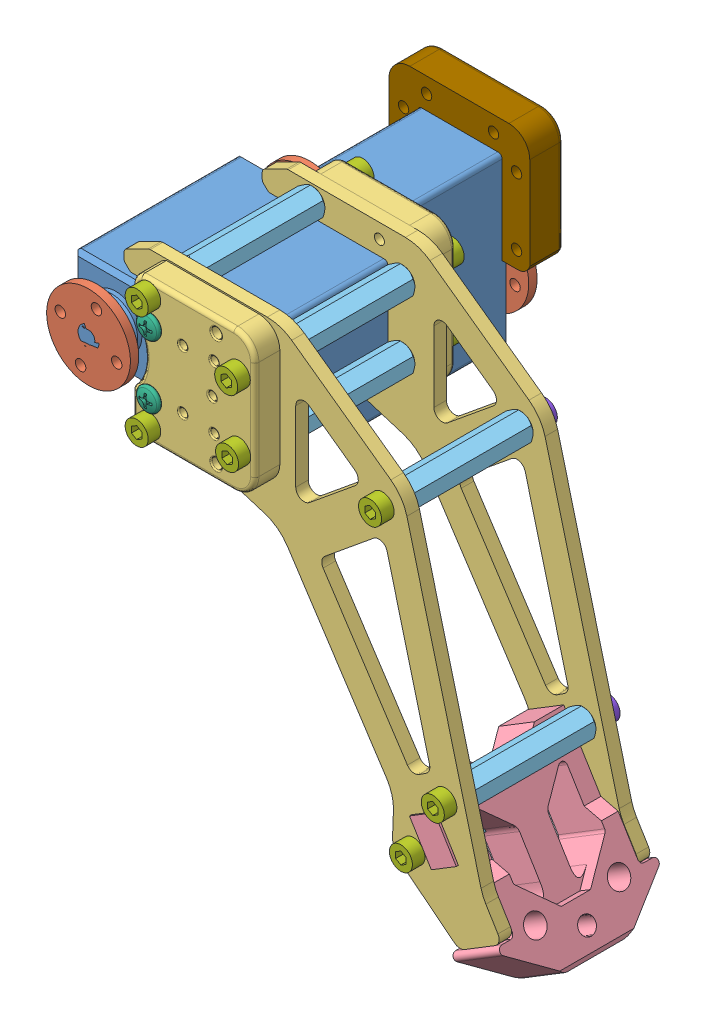
SolidWorks assembly ServoASM, configuration По умолчанию. Lengths in mm.
Overall size (131.49 117.47 116.79).
37 component instances, 9 part files, 80 mates.
Components (placement in the parent):
- RDS3115MG-1: RDS3115MG [00] at origin size (40 20 52)
- Servo_Disk_25T-1: Servo_Disk_25T [00] at (-10 0 46.5) x (-0.87183 -0.489808 0) z (0.489808 -0.87183 0) size (20 4.5 20)
- Servo_Disk_25T-2: Servo_Disk_25T [00] at (-10 0 -6.4) x (0.87183 0.489808 0) z (0.489808 -0.87183 0) size (20 4.5 20)
- Tibia_side_plate-1: Tibia_side_plate [Défaut] at (7.75 0 2) size (89.6 107.6 3)
- Foot-1: Foot [Défaut] at (59.1952 -69.5736 20) x (0 0 -1) z (0.853181 0.521616 0) size (37.94 40 13.02)
- Tibia_side_plate-3: Tibia_side_plate [Défaut] at (7.75 0 35) size (89.6 107.6 3)
- Tibia_side_plate-4: Tibia_side_plate [right] at (7.75 0 38) x (1 0 0) z (0 0 -1) size (29.2 33.65 6)
- Tibia_side_plate-5: Tibia_side_plate [right] at (7.75 0 2) size (29.2 33.65 6)
- Standoff-1: Standoff [Défaut] at (51.75 -8.1461 5) size (6 7.62 30)
- Standoff-2: Standoff [Défaut] at (59.1257 -75.9595 5) size (6 7.62 30)
- Standoff-3: Standoff [Défaut] at (66.75 -61.8929 5) size (6 7.62 30)
- BHS_M2_6X8-1: BHS_M2_6X8 [Défaut] at (2.5 7.5 44) x (1 0 0) z (0 -1 0) size (5.5 9.6 5.5)
- BHS_M2_6X8-2: BHS_M2_6X8 [Défaut] at (2.5 -7.5 44) x (1 0 0) z (0 -1 0) size (5.5 9.6 5.5)
- BHS_M2_6X8-4: BHS_M2_6X8 [Défaut] at (10 7 -4) x (-0.923728 -0.383049 0) z (0.383049 -0.923728 0) size (5.5 9.6 5.5)
- BHS_M2_6X8-5: BHS_M2_6X8 [Défaut] at (10 -7 -4) x (-0.923728 -0.383049 0) z (0.383049 -0.923728 0) size (5.5 9.6 5.5)
- M3x10-1: M3x10 [00] at (2 -13.5 44) size (5.5 5.5 13.08)
- M3x10-2: M3x10 [00] at (23.5 -8 43.8922) size (5.5 5.5 13.08)
- M3x10-3: M3x10 [00] at (2 13.5 44) size (5.5 5.5 13.08)
- M3x10-4: M3x10 [00] at (23.5 8 44.1078) size (5.5 5.5 13.08)
- M3x8-7: M3x8 [00] at (59.1257 -75.9595 2) x (-0.923728 -0.383049 0) z (0 0 -1) size (5.5 5.5 11.08)
- M3x8-8: M3x8 [00] at (51.75 -8.1461 2) x (-0.923728 -0.383049 0) z (0 0 -1) size (5.5 5.5 11.08)
- M3x8-9: M3x8 [00] at (66.75 -61.8929 2) x (-0.923728 -0.383049 0) z (0 0 -1) size (5.5 5.5 11.08)
- M3x10-5: M3x10 [00] at (51.75 -8.1461 38) size (5.5 5.5 13.08)
- M3x10-6: M3x10 [00] at (66.75 -61.8929 38) size (5.5 5.5 13.08)
- M3x10-7: M3x10 [00] at (59.1257 -75.9595 38) size (5.5 5.5 13.08)
- M3x10-8: M3x10 [00] at (23.5 8 -4) x (-0.923728 -0.383049 0) z (0 0 -1) size (5.5 5.5 13.08)
- M3x10-9: M3x10 [00] at (2 -13.5 -4) x (-0.923728 -0.383049 0) z (0 0 -1) size (5.5 5.5 13.08)
- M3x10-10: M3x10 [00] at (23.5 -8 -4) x (-0.923728 -0.383049 0) z (0 0 -1) size (5.5 5.5 13.08)
- M3x10-11: M3x10 [00] at (2 13.5 -4) x (-0.923728 -0.383049 0) z (0 0 -1) size (5.5 5.5 13.08)
- Standoff-4: Standoff [Défaut] at (23.5 8 5) size (6 7.62 30)
- Standoff-5: Standoff [Défaut] at (23.5 -8 5) size (6 7.62 30)
- Standoff-6: Standoff [Défaut] at (2 -13.5 5) size (6 7.62 30)
- Standoff-7: Standoff [Défaut] at (2 13.5 5) size (6 7.62 30)
- RDS3115MG-2: RDS3115MG [00] at (-29.0274 -40.5678 -63.286) x (0 1 0) z (0 0 1) size (40 20 52)
- Servo_Disk_25T-3: Servo_Disk_25T [00] at (-29.0274 -50.5678 -69.686) x (0.87183 0.489808 0) z (0.489808 -0.87183 0) size (20 4.5 20)
- Servo_Disk_25T-4: Servo_Disk_25T [00] at (-29.0274 -50.5678 -16.786) x (-0.87183 -0.489808 0) z (0.489808 -0.87183 0) size (20 4.5 20)
- Tibia_side_plate2-1: Tibia_side_plate2 [two] at (-29.0274 -32.8178 -61.286) x (0 1 0) z (0 0 1) size (29.2 33.65 8)
Mates (geometry in assembly coordinates):
- Концентричный1: concentric aligned: cylinder of RDS3115MG-1 through (-10 0 40) axis (0 0 1) radius 3; cylinder of Servo_Disk_25T-1 through (-10 0 42) axis (0 0 1) radius 4.5
- Совпадение1: coincident anti-aligned: plane of RDS3115MG-1 through (-10 0 42) normal (0 0 1); plane of Servo_Disk_25T-1 through (-10 0 42) normal (0 0 -1)
- Концентричный2: concentric anti-aligned: cylinder of RDS3115MG-1 through (-10 0 -10.6191) axis (0 0 1) radius 1; cylinder of Servo_Disk_25T-2 through (-10 0 -1.9) axis (0 0 -1) radius 4.5
- Совпадение2: coincident anti-aligned: plane of RDS3115MG-1 through (-10 0 -5.5) normal (0 0 -1); plane of Servo_Disk_25T-2 through (-10 0 -5.5) normal (0 0 1)
- Концентричный3: concentric anti-aligned: cylinder of Servo_Disk_25T-1 through (-3.2602 -1.8909 44.5) axis (0 0 -1) radius 1.25; cylinder of Servo_Disk_25T-2 through (-3.2602 -1.8909 -4.4) axis (0 0 1) radius 1.25
- Концентричный4: concentric anti-aligned: cylinder of Tibia_side_plate-1 through (18 13.5 5) axis (0 0 1) radius 1.2; cylinder of Tibia_side_plate-5 through (18 13.5 5.5355) axis (0 0 -1) radius 1.25
- Концентричный5: concentric aligned: cylinder of Tibia_side_plate-1 through (2 -13.5 8.3941) axis (0 0 -1) radius 1.2; cylinder of Tibia_side_plate-5 through (2 -13.5 5.5355) axis (0 0 -1) radius 1.25
- Совпадение14: coincident anti-aligned: plane of Tibia_side_plate-1 through (7.75 0 2) normal (0 0 -1); plane of Tibia_side_plate-5 through (1 14 2) normal (0 0 1)
- Концентричный6: concentric aligned: cylinder of Tibia_side_plate-3 through (18 13.5 38) axis (0 0 1) radius 1.2; cylinder of Tibia_side_plate-4 through (18 13.5 34.4645) axis (0 0 1) radius 1.25
- Концентричный7: concentric anti-aligned: cylinder of Tibia_side_plate-3 through (2 -13.5 41.3941) axis (0 0 -1) radius 1.2; cylinder of Tibia_side_plate-4 through (2 -13.5 34.4645) axis (0 0 1) radius 1.25
- Совпадение15: coincident anti-aligned: plane of Tibia_side_plate-3 through (7.75 0 38) normal (0 0 1); plane of Tibia_side_plate-4 through (1 -14 38) normal (0 0 -1)
- Ширина3: width anti-aligned: plane of RDS3115MG-1 through (20 10 0) normal (0 1 0); plane of RDS3115MG-1 through (-20 -10 0) normal (0 -1 0); plane of Tibia_side_plate-3 through (7.75 10 38) normal (0 -1 0); plane of Tibia_side_plate-3 through (7.75 -10 38) normal (0 1 0)
- Ширина4: width aligned: plane of RDS3115MG-1 through (-20 -10 0) normal (0 -1 0); plane of RDS3115MG-1 through (20 10 0) normal (0 1 0); plane of Tibia_side_plate-1 through (7.75 10 5) normal (0 -1 0); plane of Tibia_side_plate-1 through (7.75 -10 5) normal (0 1 0)
- Концентричный8: concentric aligned: cylinder of RDS3115MG-1 through (17.5 7.5 40) axis (0 0 -1) radius 1; cylinder of Tibia_side_plate-4 through (17.5 7.5 44) axis (0 0 -1) radius 1
- Концентричный9: concentric aligned: cylinder of RDS3115MG-1 through (2.5 -7.5 40) axis (0 0 -1) radius 1; cylinder of Tibia_side_plate-4 through (2.5 -7.5 44) axis (0 0 -1) radius 1
- Концентричный10: concentric aligned: cylinder of RDS3115MG-1 through (10 7 0) axis (0 0 1) radius 1; cylinder of Tibia_side_plate-5 through (10 7 -4) axis (0 0 1) radius 1
- Концентричный11: concentric aligned: cylinder of RDS3115MG-1 through (10 -7 0) axis (0 0 1) radius 1; cylinder of Tibia_side_plate-5 through (10 -7 -4) axis (0 0 1) radius 1
- Совпадение16: coincident anti-aligned: plane of RDS3115MG-1 through (0 0 0) normal (0 0 -1); plane of Tibia_side_plate-5 through (1 14 0) normal (0 0 1)
- Совпадение17: coincident anti-aligned: plane of RDS3115MG-1 through (0 0 40) normal (0 0 1); plane of Tibia_side_plate-4 through (1 -14 40) normal (0 0 -1)
- Совпадение18: coincident anti-aligned: plane of Foot-1 through (59.1952 -69.5736 20) normal (-0.853181 -0.521616 0); plane of Tibia_side_plate-3 through (58.6736 -68.7204 34.999) normal (0.853181 0.521616 0)
- Совпадение19: coincident anti-aligned: plane of Tibia_side_plate-1 through (58.6736 -68.7204 1.999) normal (0.853181 0.521616 0); plane of Foot-1 through (59.1952 -69.5736 20) normal (-0.853181 -0.521616 0)
- Совпадение20: coincident anti-aligned: plane of Foot-1 through (64.6459 -65.0691 20) normal (-0.521616 0.853181 0); plane of Tibia_side_plate-3 through (58.6736 -68.7204 34.999) normal (0.521616 -0.853181 0)
- Ширина5: width aligned: plane of Foot-1 through (59.1952 -69.5736 35) normal (0 0 1); plane of Foot-1 through (59.1952 -69.5736 5) normal (0 0 -1); plane of Tibia_side_plate-1 through (7.75 0 5) normal (0 0 1); plane of Tibia_side_plate-3 through (7.75 0 35) normal (0 0 -1)
- Концентричный12: concentric aligned: cylinder of Tibia_side_plate-3 through (51.75 -8.1461 35) axis (0 0 -1) radius 1.7; cylinder of Standoff-1 through (51.75 -8.1461 5) axis (0 0 -1) radius 1.25
- Ширина6: width aligned: plane of Tibia_side_plate-1 through (7.75 0 5) normal (0 0 1); plane of Tibia_side_plate-3 through (7.75 0 35) normal (0 0 -1); plane of Standoff-1 through (51.75 -8.1461 35) normal (0 0 1); plane of Standoff-1 through (51.75 -8.1461 5) normal (0 0 -1)
- Ширина7: width aligned: plane of Tibia_side_plate-1 through (7.75 0 5) normal (0 0 1); plane of Tibia_side_plate-3 through (7.75 0 35) normal (0 0 -1); plane of Standoff-3 through (66.75 -61.8929 35) normal (0 0 1); plane of Standoff-3 through (66.75 -61.8929 5) normal (0 0 -1)
- Ширина8: width aligned: plane of Tibia_side_plate-3 through (7.75 0 35) normal (0 0 -1); plane of Tibia_side_plate-1 through (7.75 0 5) normal (0 0 1); plane of Standoff-2 through (59.1257 -75.9595 5) normal (0 0 -1); plane of Standoff-2 through (59.1257 -75.9595 35) normal (0 0 1)
- Концентричный13: concentric aligned: cylinder of Tibia_side_plate-3 through (59.1257 -75.9595 35) axis (0 0 -1) radius 1.7; cylinder of Standoff-2 through (59.1257 -75.9595 5) axis (0 0 -1) radius 1.25
- Концентричный14: concentric aligned: cylinder of Tibia_side_plate-3 through (66.75 -61.8929 35) axis (0 0 -1) radius 1.7; cylinder of Standoff-3 through (66.75 -61.8929 5) axis (0 0 -1) radius 1.25
- Концентричный15: concentric aligned: cylinder of Tibia_side_plate-4 through (2.5 7.5 44) axis (0 0 -1) radius 1; cylinder of BHS_M2_6X8-1 through (2.5 7.5 46.08) axis (0 0 -1) radius 1.3
- Совпадение21: coincident anti-aligned: plane of Tibia_side_plate-4 through (1 -14 44) normal (0 0 1); plane of BHS_M2_6X8-1 through (2.5 7.5 44) normal (0 0 -1)
- Концентричный16: concentric aligned: cylinder of Tibia_side_plate-4 through (2.5 -7.5 44) axis (0 0 -1) radius 1; cylinder of BHS_M2_6X8-2 through (2.5 -7.5 46.08) axis (0 0 -1) radius 1.3
- Совпадение22: coincident anti-aligned: plane of Tibia_side_plate-4 through (1 -14 44) normal (0 0 1); plane of BHS_M2_6X8-2 through (2.5 -7.5 44) normal (0 0 -1)
- Концентричный17: concentric aligned: cylinder of Tibia_side_plate-5 through (10 7 -4) axis (0 0 1) radius 1; cylinder of BHS_M2_6X8-4 through (10 7 -6.08) axis (0 0 1) radius 1.3
- Совпадение23: coincident anti-aligned: plane of Tibia_side_plate-5 through (1 14 -4) normal (0 0 -1); plane of BHS_M2_6X8-4 through (10 7 -4) normal (0 0 1)
- Совпадение24: coincident anti-aligned: plane of Tibia_side_plate-5 through (1 14 -4) normal (0 0 -1); plane of BHS_M2_6X8-5 through (10 -7 -4) normal (0 0 1)
- Концентричный18: concentric aligned: cylinder of Tibia_side_plate-5 through (10 -7 -4) axis (0 0 1) radius 1; cylinder of BHS_M2_6X8-5 through (10 -7 -6.08) axis (0 0 1) radius 1.3
- Совпадение25: coincident anti-aligned: plane of Tibia_side_plate-4 through (1 -14 44) normal (0 0 1); plane of M3x10-1 through (-0.783 -16.283 44) normal (0 0 -1)
- Концентричный19: concentric anti-aligned: cylinder of Tibia_side_plate-4 through (2 -13.5 34.4645) axis (0 0 1) radius 1.25; cylinder of M3x10-1 through (2 -13.5 47.3) axis (0 0 -1) radius 2.75
- Ширина9: width aligned: plane of M3x10-3 through (-0.783 10.717 44) normal (0 0 -1); plane of Tibia_side_plate-4 through (1 -14 44) normal (0 0 1); plane of M3x10-2 through (20.717 -10.783 43.8922) normal (0 0 -1); plane of M3x10-4 through (20.717 5.217 44.1078) normal (0 0 -1)
- Концентричный20: concentric anti-aligned: cylinder of Tibia_side_plate-4 through (2 13.5 34.4645) axis (0 0 1) radius 1.25; cylinder of M3x10-3 through (2 13.5 47.3) axis (0 0 -1) radius 2.75
- Концентричный21: concentric anti-aligned: cylinder of Tibia_side_plate-4 through (23.5 -8 34.4645) axis (0 0 1) radius 1.25; cylinder of M3x10-2 through (23.5 -8 47.1922) axis (0 0 -1) radius 2.75
- Концентричный22: concentric anti-aligned: cylinder of Tibia_side_plate-4 through (23.5 8 34.4645) axis (0 0 1) radius 1.25; cylinder of M3x10-4 through (23.5 8 47.4078) axis (0 0 -1) radius 2.75
- Совпадение30: coincident anti-aligned: plane of Tibia_side_plate-4 through (1 -14 44) normal (0 0 1); plane of M3x10-3 through (-0.783 10.717 44) normal (0 0 -1)
- Концентричный27: concentric anti-aligned: cylinder of Tibia_side_plate-1 through (51.75 -8.1461 2) axis (0 0 -1) radius 1.7; cylinder of M3x8-8 through (51.75 -8.1461 -1.3) axis (0 0 1) radius 2.75
- Концентричный28: concentric anti-aligned: cylinder of Tibia_side_plate-1 through (59.1257 -75.9595 2) axis (0 0 -1) radius 1.7; cylinder of M3x8-7 through (59.1257 -75.9595 -1.3) axis (0 0 1) radius 2.75
- Концентричный29: concentric anti-aligned: cylinder of Tibia_side_plate-1 through (66.75 -61.8929 2) axis (0 0 -1) radius 1.7; cylinder of M3x8-9 through (66.75 -61.8929 -1.3) axis (0 0 1) radius 2.75
- Совпадение31: coincident anti-aligned: plane of Tibia_side_plate-1 through (7.75 0 2) normal (0 0 -1); plane of M3x8-7 through (62.7625 -77.4643 2) normal (0 0 1)
- Совпадение32: coincident anti-aligned: plane of Tibia_side_plate-1 through (7.75 0 2) normal (0 0 -1); plane of M3x8-9 through (70.3868 -63.3976 2) normal (0 0 1)
- Совпадение33: coincident anti-aligned: plane of Tibia_side_plate-1 through (7.75 0 2) normal (0 0 -1); plane of M3x8-8 through (55.3868 -9.6508 2) normal (0 0 1)
- Концентричный30: concentric aligned: cylinder of Tibia_side_plate-3 through (51.75 -8.1461 35) axis (0 0 -1) radius 1.7; cylinder of M3x10-5 through (51.75 -8.1461 41.3) axis (0 0 -1) radius 2.75
- Концентричный31: concentric aligned: cylinder of Tibia_side_plate-3 through (59.1257 -75.9595 35) axis (0 0 -1) radius 1.7; cylinder of M3x10-7 through (59.1257 -75.9595 41.3) axis (0 0 -1) radius 2.75
- Концентричный32: concentric aligned: cylinder of Tibia_side_plate-3 through (66.75 -61.8929 35) axis (0 0 -1) radius 1.7; cylinder of M3x10-6 through (66.75 -61.8929 41.3) axis (0 0 -1) radius 2.75
- Совпадение34: coincident anti-aligned: plane of Tibia_side_plate-3 through (7.75 0 38) normal (0 0 1); plane of M3x10-5 through (48.967 -10.9291 38) normal (0 0 -1)
- Совпадение35: coincident anti-aligned: plane of Tibia_side_plate-3 through (7.75 0 38) normal (0 0 1); plane of M3x10-6 through (63.967 -64.6759 38) normal (0 0 -1)
- Совпадение36: coincident anti-aligned: plane of Tibia_side_plate-3 through (7.75 0 38) normal (0 0 1); plane of M3x10-7 through (56.3427 -78.7425 38) normal (0 0 -1)
- Совпадение37: coincident anti-aligned: plane of Tibia_side_plate-5 through (1 14 -4) normal (0 0 -1); plane of M3x10-8 through (27.1368 6.4953 -4) normal (0 0 1)
- Концентричный33: concentric anti-aligned: cylinder of Tibia_side_plate-5 through (23.5 8 5.5355) axis (0 0 -1) radius 1.25; cylinder of M3x10-8 through (23.5 8 -7.3) axis (0 0 1) radius 2.75
- Концентричный34: concentric anti-aligned: cylinder of Tibia_side_plate-5 through (2 13.5 5.5355) axis (0 0 -1) radius 1.25; cylinder of M3x10-11 through (2 13.5 -7.3) axis (0 0 1) radius 2.75
- Концентричный35: concentric anti-aligned: cylinder of Tibia_side_plate-5 through (2 -13.5 5.5355) axis (0 0 -1) radius 1.25; cylinder of M3x10-9 through (2 -13.5 -7.3) axis (0 0 1) radius 2.75
- Концентричный36: concentric anti-aligned: cylinder of Tibia_side_plate-5 through (23.5 -8 5.5355) axis (0 0 -1) radius 1.25; cylinder of M3x10-10 through (23.5 -8 -7.3) axis (0 0 1) radius 2.75
- Совпадение38: coincident anti-aligned: plane of Tibia_side_plate-5 through (1 14 -4) normal (0 0 -1); plane of M3x10-10 through (27.1368 -9.5047 -4) normal (0 0 1)
- Совпадение39: coincident anti-aligned: plane of Tibia_side_plate-5 through (1 14 -4) normal (0 0 -1); plane of M3x10-9 through (5.6368 -15.0047 -4) normal (0 0 1)
- Совпадение40: coincident anti-aligned: plane of Tibia_side_plate-5 through (1 14 -4) normal (0 0 -1); plane of M3x10-11 through (5.6368 11.9953 -4) normal (0 0 1)
- Концентричный45: concentric aligned: cylinder of M3x10-4 through (23.5 8 47.4078) axis (0 0 -1) radius 2.75; cylinder of Standoff-4 through (23.5 8 5) axis (0 0 -1) radius 1.25
- Совпадение49: coincident anti-aligned: plane of Tibia_side_plate-3 through (7.75 0 35) normal (0 0 -1); plane of Standoff-4 through (23.5 8 35) normal (0 0 1)
- Совпадение50: coincident anti-aligned: plane of Tibia_side_plate-1 through (7.75 0 5) normal (0 0 1); plane of Standoff-5 through (23.5 -8 5) normal (0 0 -1)
- Совпадение51: coincident anti-aligned: plane of Tibia_side_plate-3 through (7.75 0 35) normal (0 0 -1); plane of Standoff-6 through (2 -13.5 35) normal (0 0 1)
- Совпадение52: coincident anti-aligned: plane of Tibia_side_plate-1 through (7.75 0 5) normal (0 0 1); plane of Standoff-7 through (2 13.5 5) normal (0 0 -1)
- Концентричный46: concentric aligned: cylinder of M3x10-2 through (23.5 -8 47.1922) axis (0 0 -1) radius 2.75; cylinder of Standoff-5 through (23.5 -8 5) axis (0 0 -1) radius 1.25
- Концентричный47: concentric aligned: cylinder of M3x10-1 through (2 -13.5 47.3) axis (0 0 -1) radius 2.75; cylinder of Standoff-6 through (2 -13.5 5) axis (0 0 -1) radius 1.25
- Концентричный48: concentric aligned: cylinder of M3x10-3 through (2 13.5 47.3) axis (0 0 -1) radius 2.75; cylinder of Standoff-7 through (2 13.5 5) axis (0 0 -1) radius 1.25
- Концентричный73: concentric aligned: cylinder of RDS3115MG-2 through (-29.0274 -50.5678 -23.286) axis (0 0 1) radius 3; cylinder of Servo_Disk_25T-4 through (-29.0274 -50.5678 -18.786) axis (0 0 1) radius 10
- Концентричный74: concentric anti-aligned: cylinder of Servo_Disk_25T-3 through (-29.0274 -50.5678 -67.686) axis (0 0 -1) radius 10; cylinder of Servo_Disk_25T-4 through (-29.0274 -50.5678 -18.786) axis (0 0 1) radius 10
- Совпадение53: coincident anti-aligned: plane of RDS3115MG-2 through (-29.0274 -50.5678 -68.786) normal (0 0 -1); plane of Servo_Disk_25T-3 through (-29.0274 -50.5678 -68.786) normal (0 0 1)
- Совпадение54: coincident anti-aligned: plane of RDS3115MG-2 through (-29.0274 -50.5678 -21.286) normal (0 0 1); plane of Servo_Disk_25T-4 through (-29.0274 -50.5678 -21.286) normal (0 0 -1)
- Концентричный75: concentric anti-aligned: cylinder of Servo_Disk_25T-3 through (-35.7672 -48.6769 -67.686) axis (0 0 1) radius 1.25; cylinder of Servo_Disk_25T-4 through (-35.7672 -48.6769 -18.786) axis (0 0 -1) radius 1.25
- Концентричный80: concentric aligned: cylinder of RDS3115MG-2 through (-22.0274 -30.5678 -63.286) axis (0 0 1) radius 1; cylinder of Tibia_side_plate2-1 through (-22.0274 -30.5678 -69.286) axis (0 0 1) radius 1
- Концентричный81: concentric aligned: cylinder of RDS3115MG-2 through (-36.0274 -30.5678 -63.286) axis (0 0 1) radius 1; cylinder of Tibia_side_plate2-1 through (-36.0274 -30.5678 -69.286) axis (0 0 1) radius 1
- Совпадение57: coincident anti-aligned: plane of RDS3115MG-2 through (-29.0274 -40.5678 -63.286) normal (0 0 -1); plane of Tibia_side_plate2-1 through (-43.0274 -39.5678 -63.286) normal (0 0 1)
